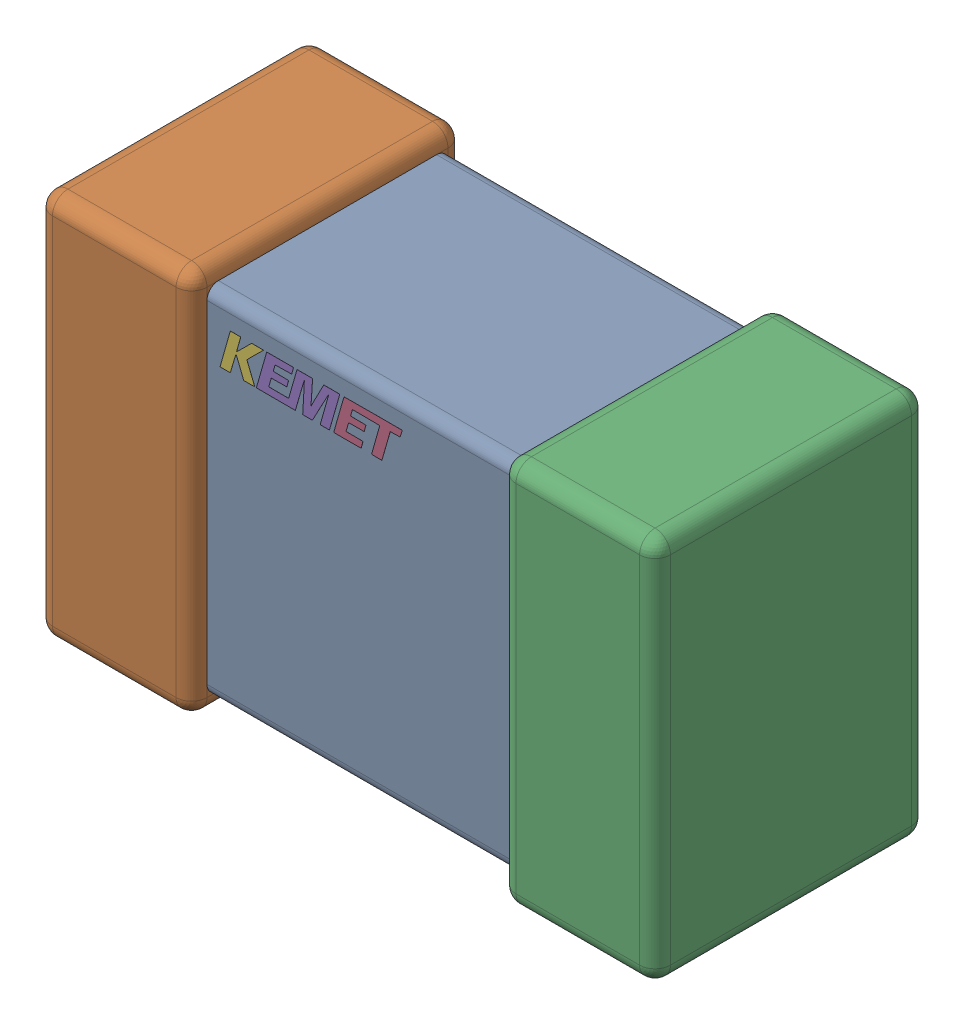
SolidWorks assembly C18.step, configuration Default. Lengths in mm.
Overall size (2 1.25 0.88).
3 component instances, 3 part files, 0 mates.
Components (placement in the parent):
- Cap_KEMET_C0805C472J3HAC_eec.step-1: Cap_KEMET_C0805C472J3HAC_eec.step [Default] at (56.841 51.181 0) size (1 1.15 0.78)
- Cap_KEMET_C0805C472J3HAC_eec-7.step-1: Cap_KEMET_C0805C472J3HAC_eec-7.step [Default] at (56.841 51.181 0) size (2 1.25 0.88)
- Cap_KEMET_C0805C472J3HAC_eec-8.step-1: Cap_KEMET_C0805C472J3HAC_eec-8.step [Default] at (56.841 51.181 0) size (0.59 0.12 0)
